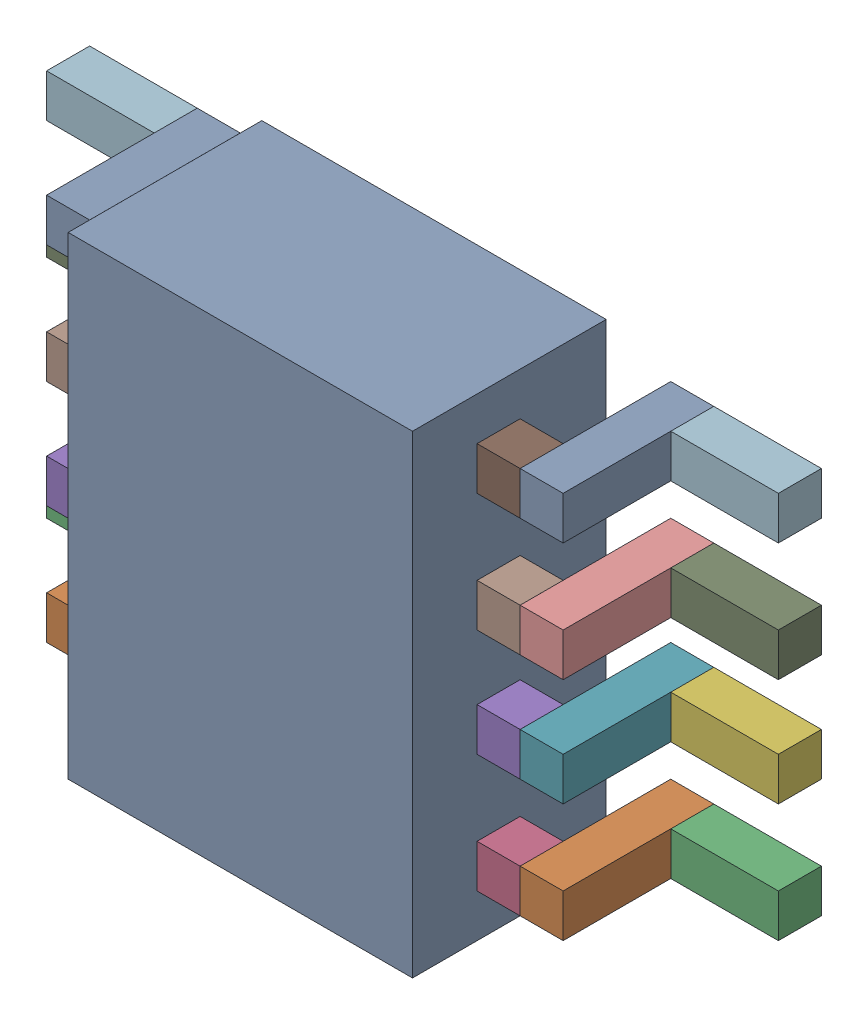
SolidWorks assembly U33, configuration Default. Lengths in mm.
Overall size (3.4 2.2 1).
50 component instances, 4 part files, 0 mates.
Components (placement in the parent):
- 836755568-1: 836755568 [Default] at (128.65 20.65 0.1) size (1.6 2.2 0.9)
  - Extruded_45-1: Extruded_45 [Default] at origin size (1.6 2.2 0.9)
- 836755056-1: 836755056 [Default] at (129.7499 19.8501 0) size (0.2 0.2 0.7)
  - Extruded_28-1: Extruded_28 [Default] at origin size (0.2 0.2 0.7)
- 836755312-1: 836755312 [Default] at (130.0999 19.8501 0) size (0.5 0.2 0.2)
  - Extruded_46-1: Extruded_46 [Default] at origin size (0.5 0.2 0.2)
- 836755440-1: 836755440 [Default] at (129.5499 19.8501 0.5) size (0.2 0.2 0.2)
  - Extruded_30-1: Extruded_30 [Default] at origin size (0.2 0.2 0.2)
- 836755440-2: 836755440 [Default] at (129.5499 20.4001 0.5) size (0.2 0.2 0.2)
  - Extruded_30-1: Extruded_30 [Default] at origin size (0.2 0.2 0.2)
- 836755312-2: 836755312 [Default] at (130.0999 20.4001 0) size (0.5 0.2 0.2)
  - Extruded_46-1: Extruded_46 [Default] at origin size (0.5 0.2 0.2)
- 836755056-2: 836755056 [Default] at (129.7499 20.4001 0) size (0.2 0.2 0.7)
  - Extruded_28-1: Extruded_28 [Default] at origin size (0.2 0.2 0.7)
- 836755440-3: 836755440 [Default] at (129.5499 20.9001 0.5) size (0.2 0.2 0.2)
  - Extruded_30-1: Extruded_30 [Default] at origin size (0.2 0.2 0.2)
- 836755312-3: 836755312 [Default] at (130.0999 20.9001 0) size (0.5 0.2 0.2)
  - Extruded_46-1: Extruded_46 [Default] at origin size (0.5 0.2 0.2)
- 836755056-3: 836755056 [Default] at (129.7499 20.9001 0) size (0.2 0.2 0.7)
  - Extruded_28-1: Extruded_28 [Default] at origin size (0.2 0.2 0.7)
- 836755440-4: 836755440 [Default] at (129.5499 21.4501 0.5) size (0.2 0.2 0.2)
  - Extruded_30-1: Extruded_30 [Default] at origin size (0.2 0.2 0.2)
- 836755312-4: 836755312 [Default] at (130.0999 21.4501 0) size (0.5 0.2 0.2)
  - Extruded_46-1: Extruded_46 [Default] at origin size (0.5 0.2 0.2)
- 836755056-4: 836755056 [Default] at (129.7499 21.4501 0) size (0.2 0.2 0.7)
  - Extruded_28-1: Extruded_28 [Default] at origin size (0.2 0.2 0.7)
- 836755056-5: 836755056 [Default] at (127.5499 19.8501 0) size (0.2 0.2 0.7)
  - Extruded_28-1: Extruded_28 [Default] at origin size (0.2 0.2 0.7)
- 836755312-5: 836755312 [Default] at (127.1999 19.8501 0) size (0.5 0.2 0.2)
  - Extruded_46-1: Extruded_46 [Default] at origin size (0.5 0.2 0.2)
- 836755440-5: 836755440 [Default] at (127.7499 19.8501 0.5) size (0.2 0.2 0.2)
  - Extruded_30-1: Extruded_30 [Default] at origin size (0.2 0.2 0.2)
- 836755056-6: 836755056 [Default] at (127.5499 20.4001 0) size (0.2 0.2 0.7)
  - Extruded_28-1: Extruded_28 [Default] at origin size (0.2 0.2 0.7)
- 836755312-6: 836755312 [Default] at (127.1999 20.4001 0) size (0.5 0.2 0.2)
  - Extruded_46-1: Extruded_46 [Default] at origin size (0.5 0.2 0.2)
- 836755440-6: 836755440 [Default] at (127.7499 20.4001 0.5) size (0.2 0.2 0.2)
  - Extruded_30-1: Extruded_30 [Default] at origin size (0.2 0.2 0.2)
- 836755056-7: 836755056 [Default] at (127.5499 20.9001 0) size (0.2 0.2 0.7)
  - Extruded_28-1: Extruded_28 [Default] at origin size (0.2 0.2 0.7)
- 836755312-7: 836755312 [Default] at (127.1999 20.9001 0) size (0.5 0.2 0.2)
  - Extruded_46-1: Extruded_46 [Default] at origin size (0.5 0.2 0.2)
- 836755440-7: 836755440 [Default] at (127.7499 20.9001 0.5) size (0.2 0.2 0.2)
  - Extruded_30-1: Extruded_30 [Default] at origin size (0.2 0.2 0.2)
- 836755440-8: 836755440 [Default] at (127.7499 21.4501 0.5) size (0.2 0.2 0.2)
  - Extruded_30-1: Extruded_30 [Default] at origin size (0.2 0.2 0.2)
- 836755312-8: 836755312 [Default] at (127.1999 21.4501 0) size (0.5 0.2 0.2)
  - Extruded_46-1: Extruded_46 [Default] at origin size (0.5 0.2 0.2)
- 836755056-8: 836755056 [Default] at (127.5499 21.4501 0) size (0.2 0.2 0.7)
  - Extruded_28-1: Extruded_28 [Default] at origin size (0.2 0.2 0.7)
